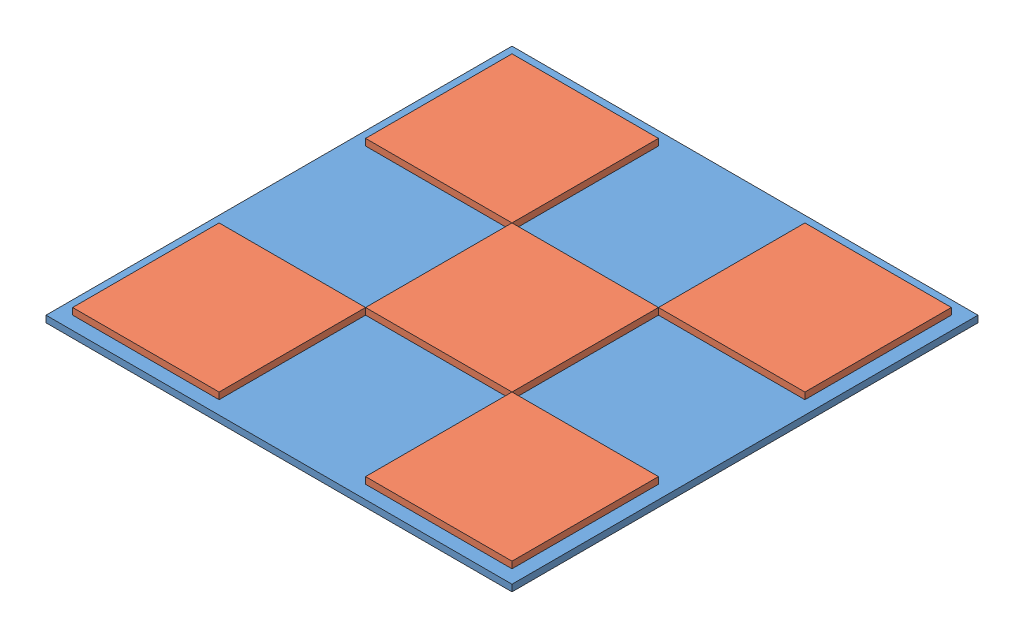
SolidWorks assembly ddrpad, configuration Default. Lengths in mm.
Overall size (889 25.4 889).
6 component instances, 2 part files, 15 mates.
Components (placement in the parent):
- base-1: base [Default] at (-501.3543 20.0875 456.54) size (889 12.7 889)
- button-1: button [Default] at (-475.9543 32.7875 431.14) size (279.4 12.7 279.4)
- button-4: button [Default] at (82.8457 32.7875 -127.66) size (279.4 12.7 279.4)
- button-5: button [Default] at (-196.5543 32.7875 -127.66) x (0 0 -1) z (1 0 0) size (279.4 12.7 279.4)
- button-6: button [Default] at (82.8457 32.7875 431.14) size (279.4 12.7 279.4)
- button-8: button [Default] at (-196.5543 32.7875 151.74) size (279.4 12.7 279.4)
Mates (geometry in assembly coordinates):
- Coincident1: coincident anti-aligned: plane of base-1 through (-501.3543 32.7875 456.54) normal (0 1 0); plane of button-1 through (-475.9543 32.7875 431.14) normal (0 -1 0)
- Distance1: distance = 25.4 mm: line of button-1 through (-475.9543 32.7875 431.14) axis (1 0 0); line of base-1 through (-501.3543 32.7875 456.54) axis (1 0 0)
- Distance2: distance = 25.4 mm: line of button-1 through (-475.9543 32.7875 151.74) axis (0 0 1); line of base-1 through (-501.3543 32.7875 -432.46) axis (0 0 1)
- Coincident6: coincident anti-aligned: plane of base-1 through (-501.3543 32.7875 456.54) normal (0 1 0); plane of button-4 through (82.8457 32.7875 -127.66) normal (0 -1 0)
- Coincident7: coincident anti-aligned: plane of base-1 through (-501.3543 32.7875 456.54) normal (0 1 0); plane of button-5 through (-196.5543 32.7875 -127.66) normal (0 -1 0)
- Coincident8: coincident anti-aligned: plane of base-1 through (-501.3543 32.7875 456.54) normal (0 1 0); plane of button-6 through (82.8457 32.7875 431.14) normal (0 -1 0)
- Distance9: distance = 25.4 mm: line of button-6 through (82.8457 32.7875 431.14) axis (1 0 0); line of base-1 through (-501.3543 32.7875 456.54) axis (1 0 0)
- Distance10: distance = 25.4 mm: line of base-1 through (387.6457 32.7875 456.54) axis (0 0 -1); line of button-6 through (362.2457 32.7875 431.14) axis (0 0 -1)
- Distance12: distance = 25.4 mm: line of button-4 through (362.2457 32.7875 -407.06) axis (-1 0 0); line of base-1 through (387.6457 32.7875 -432.46) axis (-1 0 0)
- Distance13: distance = 25.4 mm: line of button-4 through (362.2457 32.7875 -127.66) axis (0 0 -1); line of base-1 through (387.6457 32.7875 456.54) axis (0 0 -1)
- Distance14: distance = 25.4 mm: line of button-5 through (-475.9543 32.7875 -407.06) axis (0 0 1); line of base-1 through (-501.3543 32.7875 -432.46) axis (0 0 1)
- Distance15: distance = 25.4 mm: line of button-5 through (-196.5543 32.7875 -407.06) axis (-1 0 0); line of base-1 through (387.6457 32.7875 -432.46) axis (-1 0 0)
- Coincident18: coincident: plane of base-1 through (-501.3543 32.7875 456.54) normal (0 1 0); plane of button-8 through (-343.3976 32.7875 151.74) normal (0 -1 0)
- Distance16: distance = 304.8 mm: line of base-1 through (387.6457 32.7875 -432.46) axis (-1 0 0); line of button-8 through (82.8457 32.7875 -127.66) axis (-1 0 0)
- Distance17: distance = 304.8 mm: line of button-8 through (-196.5543 32.7875 -127.66) axis (0 0 1); line of base-1 through (-501.3543 32.7875 -432.46) axis (0 0 1)
